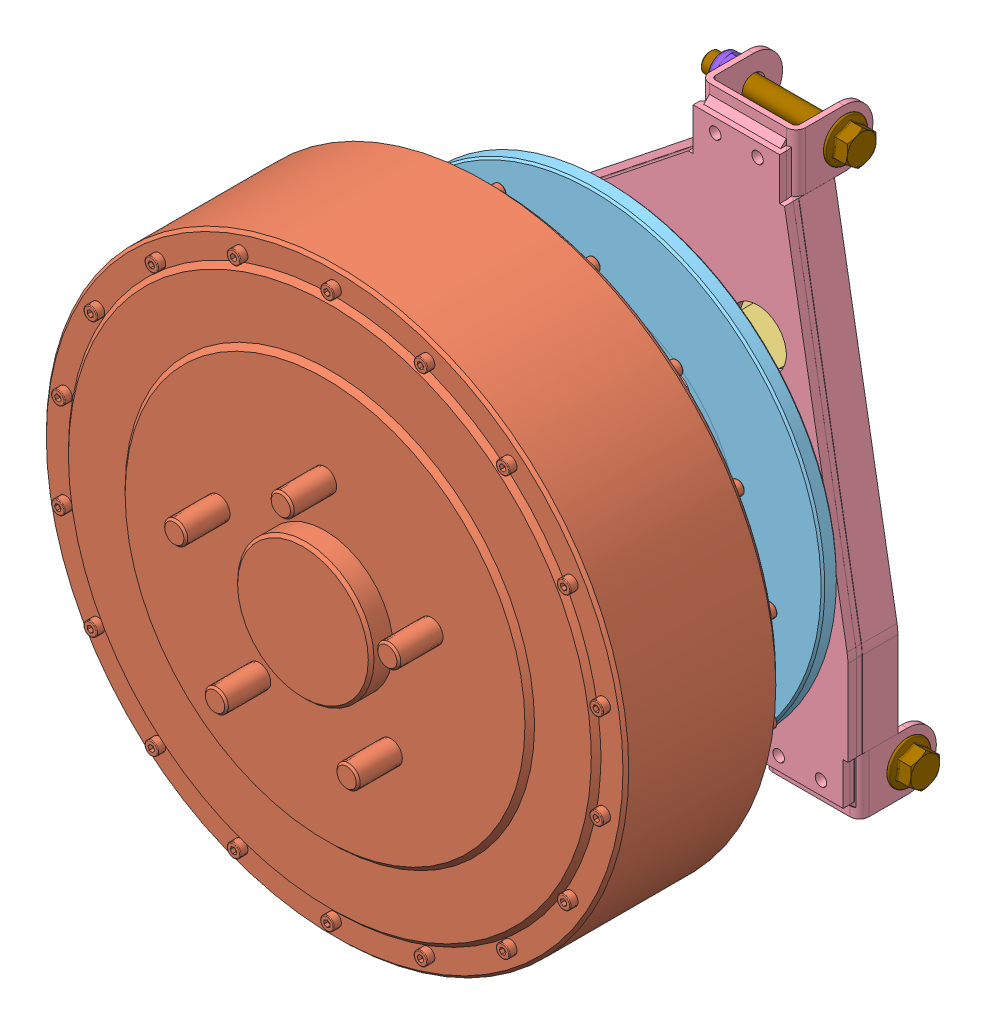
SolidWorks assembly mount of motor, configuration -0. Lengths in mm.
Overall size (303 310.5 250).
18 component instances, 9 part files, 31 mates.
Components (placement in the parent):
- Motor_QSWP96V8000W-1: Motor_QSWP96V8000W [-0] at origin size (303 303 250)
  - Motor_QSWP96V8000W-Part-1-1: Motor_QSWP96V8000W-Part-1 [Výchozí] at origin size (40 40 82.5)
  - Motor_QSWP96V8000W-Part-2-1: Motor_QSWP96V8000W-Part-2 [Výchozí] at origin size (303 303 166)
  - Motor_QSWP96V8000W-Part-3-1: Motor_QSWP96V8000W-Part-3 [Výchozí] at (0 0 -2) size (46 53.12 18.5)
- bracket-1: bracket [Výchozí<Jako obrobený>] at (0 0 -189.5) size (200 294 74.5)
- brake disc-1: brake disc [Výchozí] at (0 0 -150.5) x (-1 0 0) z (0 0 -1) size (240 240 8)
- socket countersunk head screw_iso-1: socket countersunk head screw_iso [ISO 10642 - M8 x 20 --- 20N] at (34.641 -20 -158) x (0 0 1) z (-1 0 0) size (20 15.24 15.24)
- socket countersunk head screw_iso-2: socket countersunk head screw_iso [ISO 10642 - M8 x 20 --- 20N] at (0 40 -158) x (0 0 1) z (-1 0 0) size (20 15.24 15.24)
- socket countersunk head screw_iso-3: socket countersunk head screw_iso [ISO 10642 - M8 x 20 --- 20N] at (-34.641 -20 -158) x (0 0 1) z (-1 0 0) size (20 15.24 15.24)
- pen-1: pen [Výchozí] at (22 0 -210.5) x (0 0 1) z (-1 0 0) size (30 8 8)
- prevailing torque nut flange insert-2_din-1: prevailing torque nut flange insert-2_din [DIN EN 1663 - M10 - N] at (40.4 -120 -214.5) x (0 0 1) z (-1 0 0) size (21.8 21.8 13.5)
- prevailing torque nut flange insert-2_din-2: prevailing torque nut flange insert-2_din [DIN EN 1663 - M10 - N] at (-109.6 -120 -214.5) x (0 0 1) z (-1 0 0) size (21.8 21.8 13.5)
- prevailing torque nut flange insert-2_din-3: prevailing torque nut flange insert-2_din [DIN EN 1663 - M10 - N] at (7.4 144 -214.5) x (0 0 1) z (-1 0 0) size (21.8 21.8 13.5)
- hex flange bolt_din-4: hex flange bolt_din [DIN 6921 - M10 x 70 x 70-N] at (76.2 144 -214.5) x (-1 0 0) z (0 0.924225 0.381849) size (79.2 22.3 22.3)
- hex flange bolt_din-5: hex flange bolt_din [DIN 6921 - M10 x 70 x 70-N] at (109.2 -120 -214.5) x (-1 0 0) z (0 0.924225 0.381849) size (79.2 22.3 22.3)
- hex flange bolt_din-6: hex flange bolt_din [DIN 6921 - M10 x 70 x 70-N] at (-40.8 -120 -214.5) x (-1 0 0) z (0 0.924225 0.381849) size (79.2 22.3 22.3)
- prevailing torque nut flange insert-2_din-4: prevailing torque nut flange insert-2_din [DIN EN 1663 - M10 - N] at (-60 44.45 -199.1) x (0.923728 0.383049 0) z (0 0 -1) size (21.8 21.8 13.5)
- prevailing torque nut flange insert-2_din-5: prevailing torque nut flange insert-2_din [DIN EN 1663 - M10 - N] at (-60 -44.45 -199.1) x (0.85131 0.524663 0) z (0 0 -1) size (21.8 21.8 13.5)
Mates (geometry in assembly coordinates):
- Sjednocená1: coincident aligned: plane of bracket-1 through (0 0 -189.5) normal (0 1 0); plane of assembly through (0 0 0) normal (0 1 0)
- Sjednocená2: coincident aligned: plane of bracket-1 through (0 0 -189.5) normal (1 0 0); plane of assembly through (0 0 0) normal (1 0 0)
- Vzdálenost1: distance = 39 mm anti-aligned: plane of bracket-1 through (0 0 -189.5) normal (0 0 1); plane of Motor_QSWP96V8000W-1/Motor_QSWP96V8000W-Part-2-1 through (-46.5 0 -150.5) normal (0 0 -1)
- Soustředná2: concentric aligned: cylinder of Motor_QSWP96V8000W-1/Motor_QSWP96V8000W-Part-2-1 through (0 0 26.5441) axis (0 0 1) radius 29; cylinder of brake disc-1 through (0 0 -158.5) axis (0 0 1) radius 29
- Sjednocená6: coincident anti-aligned: plane of Motor_QSWP96V8000W-1/Motor_QSWP96V8000W-Part-2-1 through (-46.5 0 -150.5) normal (0 0 -1); plane of brake disc-1 through (0 0 -150.5) normal (0 0 1)
- Sjednocená7: coincident aligned: plane of brake disc-1; plane of assembly through (0 0 0) normal (0 1 0)
- Soustředná3: concentric aligned: cylinder of Motor_QSWP96V8000W-1/Motor_QSWP96V8000W-Part-2-1 through (34.641 -20 -150.5) axis (0 0 -1) radius 3.4; cylinder of socket countersunk head screw_iso-1 through (34.641 -20 -158) axis (0 0 -1) radius 4
- Soustředná4: concentric aligned: cylinder of Motor_QSWP96V8000W-1/Motor_QSWP96V8000W-Part-2-1 through (0 40 -150.5) axis (0 0 -1) radius 3.4; cylinder of socket countersunk head screw_iso-2 through (0 40 -158) axis (0 0 -1) radius 4
- Soustředná5: concentric aligned: cylinder of Motor_QSWP96V8000W-1/Motor_QSWP96V8000W-Part-2-1 through (-34.641 -20 -150.5) axis (0 0 -1) radius 3.4; cylinder of socket countersunk head screw_iso-3 through (-34.641 -20 -158) axis (0 0 -1) radius 4
- Sjednocená8: coincident aligned: cone of brake disc-1 through (0 40 -158.5) axis (0 0 1); cone of socket countersunk head screw_iso-2 through (0 40 -156.66) axis (0 0 1)
- Sjednocená9: coincident aligned: cone of brake disc-1 through (34.641 -20 -158.5) axis (0 0 1); cone of socket countersunk head screw_iso-1 through (34.641 -20 -156.66) axis (0 0 1)
- Sjednocená10: coincident aligned: cone of brake disc-1 through (-34.641 -20 -158.5) axis (0 0 1); cone of socket countersunk head screw_iso-3 through (-34.641 -20 -156.66) axis (0 0 1)
- Sjednocená12: coincident anti-aligned: plane of Motor_QSWP96V8000W-1/Motor_QSWP96V8000W-Part-1-1 through (14 0 -217) normal (1 0 0); plane of pen-1 through (14 0 -210.5) normal (-1 0 0)
- Sjednocená13: coincident anti-aligned: plane of Motor_QSWP96V8000W-1/Motor_QSWP96V8000W-Part-1-1 through (14 4 -217) normal (0 -1 0); plane of pen-1 through (14 4 -210.5) normal (0 1 0)
- Soustředná6: concentric aligned: cylinder of Motor_QSWP96V8000W-1/Motor_QSWP96V8000W-Part-1-1 through (14 0 -188.5) axis (1 0 0) radius 4; cylinder of pen-1 through (14 0 -188.5) axis (1 0 0) radius 4
- Soustředná7: concentric aligned: cylinder of bracket-1 through (100 -120 -214.5) axis (-1 0 0) radius 6; cylinder of prevailing torque nut flange insert-2_din-1 through (65.4375 -120 -214.5) axis (-1 0 0) radius 5
- Sjednocená14: coincident anti-aligned: plane of bracket-1 through (50 -105 -229.5) normal (-1 0 0); plane of prevailing torque nut flange insert-2_din-1 through (50 -120 -230.5) normal (1 0 0)
- Soustředná8: concentric anti-aligned: cylinder of bracket-1 through (-75 -120 -214.5) axis (1 0 0) radius 15; cylinder of prevailing torque nut flange insert-2_din-2 through (-84.5625 -120 -214.5) axis (-1 0 0) radius 5
- Sjednocená15: coincident anti-aligned: plane of bracket-1 through (-100 -105 -229.5) normal (-1 0 0); plane of prevailing torque nut flange insert-2_din-2 through (-100 -120 -230.5) normal (1 0 0)
- Soustředná9: concentric aligned: cylinder of bracket-1 through (67 144 -214.5) axis (-1 0 0) radius 6; cylinder of prevailing torque nut flange insert-2_din-3 through (32.4375 144 -214.5) axis (-1 0 0) radius 5
- Sjednocená16: coincident anti-aligned: plane of bracket-1 through (17 159 -229.5) normal (-1 0 0); plane of prevailing torque nut flange insert-2_din-3 through (17 144 -230.5) normal (1 0 0)
- Soustředná13: concentric anti-aligned: cylinder of bracket-1 through (67 144 -214.5) axis (-1 0 0) radius 6; cylinder of hex flange bolt_din-4 through (76.2 144 -214.5) axis (1 0 0) radius 5
- Sjednocená20: coincident anti-aligned: plane of bracket-1 through (67 159 -229.5) normal (1 0 0); plane of hex flange bolt_din-4 through (67 140.6931 -206.496) normal (-1 0 0)
- Soustředná14: concentric anti-aligned: cylinder of bracket-1 through (100 -120 -214.5) axis (-1 0 0) radius 6; cylinder of hex flange bolt_din-5 through (109.2 -120 -214.5) axis (1 0 0) radius 5
- Sjednocená21: coincident anti-aligned: plane of bracket-1 through (100 -105 -229.5) normal (1 0 0); plane of hex flange bolt_din-5 through (100 -123.3069 -206.496) normal (-1 0 0)
- Soustředná15: concentric anti-aligned: cylinder of bracket-1 through (-50 -120 -214.5) axis (-1 0 0) radius 6; cylinder of hex flange bolt_din-6 through (-40.8 -120 -214.5) axis (1 0 0) radius 5
- Sjednocená22: coincident anti-aligned: plane of bracket-1 through (-50 -105 -229.5) normal (1 0 0); plane of hex flange bolt_din-6 through (-50 -123.3069 -206.496) normal (-1 0 0)
- Soustředná16: concentric anti-aligned: cylinder of bracket-1 through (-60 44.45 -229.5) axis (0 0 1) radius 6; cylinder of prevailing torque nut flange insert-2_din-4 through (-60 44.45 -174.0625) axis (0 0 -1) radius 5
- Sjednocená23: coincident anti-aligned: plane of bracket-1 through (-90 0 -189.5) normal (0 0 -1); plane of prevailing torque nut flange insert-2_din-4 through (-74.7796 38.3212 -189.5) normal (0 0 1)
- Soustředná17: concentric anti-aligned: cylinder of bracket-1 through (-60 -44.45 -229.5) axis (0 0 1) radius 6; cylinder of prevailing torque nut flange insert-2_din-5 through (-60 -44.45 -174.0625) axis (0 0 -1) radius 5
- Sjednocená24: coincident anti-aligned: plane of bracket-1 through (-90 0 -189.5) normal (0 0 -1); plane of prevailing torque nut flange insert-2_din-5 through (-73.621 -52.8446 -189.5) normal (0 0 1)
